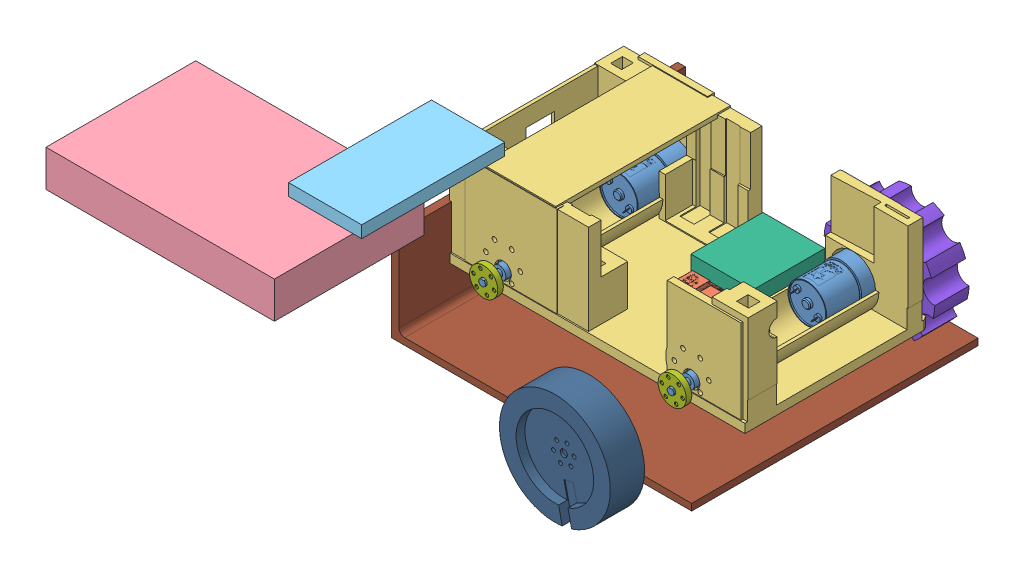
SolidWorks assembly Body, configuration Default. Lengths in mm.
Overall size (404.1 261.35 461.19).
19 component instances, 13 part files, 37 mates.
Components (placement in the parent):
- Pololu37DGearMotor-1: Pololu37DGearMotor [Default] at (433.1889 24.575 -2157.8681) x (-1 0 0) z (0 0 -1) size (36.8 36.8 107.9)
- Pololu37DGearMotor-2: Pololu37DGearMotor [Default] at (393.3389 24.575 -2043.7181) size (36.8 36.8 107.9)
- Part2-1: Part2 [Default] at origin
- Pololu37DGearMotor-3: Pololu37DGearMotor [Default] at (603.1889 24.575 -2157.8681) x (-1 0 0) z (0 0 -1) size (36.8 36.8 107.9)
- Pololu37DGearMotor-4: Pololu37DGearMotor [Default] at (563.3389 24.575 -2043.7181) size (36.8 36.8 107.9)
- RaspberryPi3-1: RaspberryPi3 [Default] at (530.3567 10.1 -2115.1676) x (0 0 1) z (0 1 0) size (89.64 57.31 18.92)
- Chassis3-1: Chassis3 [Default] at (583.2639 24.575 -2100.7931) x (-1 0 0) z (0 0 1) size (295.52 97.94 165.35)
- MaxoakPowerBank-1: MaxoakPowerBank [Default] at (250.8001 124.5785 -1906.0153) x (0 0 1) z (-1 0 0) size (135 33 206)
- MotoX-1: MotoX [Default] at (449.4488 208.455 -1791.0614) size (66.04 10.84 128.96)
- AdafruitMotorHat-1: AdafruitMotorHat [Default] at (560.7674 37.34 -2163.6096) x (0 0 1) z (1 0 0) size (65 13 56)
- Cover-1: Cover [Default] at (-302.6975 -256.127 -1471.0702) size (214.11 90 180) (hidden)
- PololuHub-2: PololuHub [Default] at (413.264 17.575 -2195.7931) x (-0.300118 -0.953902 0) z (0 0 1) size (25.4 25.4 9.2)
- PololuHub-3: PololuHub [Default] at (583.2638 17.575 -2195.7931) x (0.866025 0.5 0) z (0 0 1) size (25.4 25.4 9.2)
- PololuHub-4: PololuHub [Default] at (413.2639 17.5751 -2005.7931) x (-0.951824 -0.306645 0) z (0 0 -1) size (25.4 25.4 9.2)
- PololuHub-5: PololuHub [Default] at (583.2639 17.5751 -2005.7931) x (-0.927502 -0.373818 0) z (0 0 -1) size (25.4 25.4 9.2)
- HighTractionWheel-2: HighTractionWheel [Default] at (583.2639 17.575 -2221.1531) x (0 0 1) z (0.976357 -0.216166 0) size (30.86 100 100)
- MachineScrew4-40-1: MachineScrew4-40 [Default] at (588.0289 9.3218 -2211.1531) x (-0.989414 -0.145117 0) z (-0.145117 0.989414 0) size (5.02 20.48 5.02)
- Wheel-3: Wheel [Default] at (583.2639 17.575 -1928.3853) x (0 0 1) z (-1 0 0) size (30.86 100 100)
- ChargingDock-2: ChargingDock [Default] at (621.4227 -38.425 -2210.9825) size (270.89 86 258.22)
Mates (geometry in assembly coordinates):
- Coincident2: coincident anti-aligned: line of Pololu37DGearMotor-1 through (413.2639 17.575 -2177.7931) axis (0 0 -1); line of Pololu37DGearMotor-2 through (413.2639 17.575 -2023.7931) axis (0 0 1)
- Coincident8: coincident anti-aligned: line of Pololu37DGearMotor-3 through (583.2639 17.575 -2177.7931) axis (0 0 -1); line of Pololu37DGearMotor-4 through (583.2639 17.575 -2023.7931) axis (0 0 1)
- Coincident9: coincident aligned: line of Pololu37DGearMotor-3 through (583.2639 24.575 -2123.4931) axis (0 0 1); line of Chassis3-1 through (583.2639 24.575 -2100.7931) axis (0 0 1)
- Coincident10: coincident anti-aligned: line of Pololu37DGearMotor-4 through (583.2639 24.575 -2078.0931) axis (0 0 -1); line of Chassis3-1 through (583.2639 24.575 -2100.7931) axis (0 0 1)
- Coincident11: coincident aligned: line of Pololu37DGearMotor-1 through (413.2639 24.575 -2123.4931) axis (0 0 1); line of Chassis3-1 through (413.2639 24.575 -2100.7931) axis (0 0 1)
- Coincident12: coincident anti-aligned: line of Pololu37DGearMotor-2 through (413.2639 24.575 -2078.0931) axis (0 0 -1); line of Chassis3-1 through (413.2639 24.575 -2100.7931) axis (0 0 1)
- Distance1: distance = 27.57 mm anti-aligned: plane of RaspberryPi3-1 through (560.7674 9.77 -2078.6854) normal (0 -1 0); plane of AdafruitMotorHat-1 through (560.7674 37.34 -2163.6096) normal (0 1 0)
- Coincident17: coincident aligned: plane of RaspberryPi3-1 through (550.4322 9.34 -2073.3322) normal (1 0 0); plane of AdafruitMotorHat-1 through (550.4322 24.34 -2155.2664) normal (1 0 0)
- Coincident18: coincident aligned: plane of RaspberryPi3-1 through (547.4422 9.34 -2155.2664) normal (0 0 -1); plane of AdafruitMotorHat-1 through (550.4322 24.34 -2155.2664) normal (0 0 -1)
- Parallel4: parallel aligned: plane of MaxoakPowerBank-1 through (456.8001 157.5785 -1906.0153) normal (1 0 0); plane of assembly through (0 0 0) normal (1 0 0)
- Parallel5: parallel anti-aligned: plane of Chassis3-1 through (583.2639 24.575 -2180.7931) normal (0 0 -1); plane of assembly through (0 0 0) normal (0 0 1)
- Coincident33: coincident: point of Pololu37DGearMotor-3; line of Chassis3-1 through (583.2639 17.575 -2100.7931) axis (0 0 1)
- Coincident34: coincident anti-aligned: line of Pololu37DGearMotor-1 through (413.2639 17.575 -2177.7931) axis (0 0 -1); line of PololuHub-2 through (413.2639 17.575 -2204.6431) axis (0 0 1)
- Coincident35: coincident anti-aligned: line of Pololu37DGearMotor-2 through (413.2639 17.575 -2023.7931) axis (0 0 1); line of PololuHub-4 through (413.2639 17.575 -1996.9431) axis (0 0 -1)
- Coincident36: coincident anti-aligned: line of Pololu37DGearMotor-4 through (583.2639 17.575 -2023.7931) axis (0 0 1); line of PololuHub-5 through (583.2639 17.575 -1996.9431) axis (0 0 -1)
- Coincident38: coincident anti-aligned: plane of Chassis3-1 through (498.2639 0 -2100.7931) normal (0 -1 0); plane of assembly through (0 0 0) normal (0 1 0)
- Coincident39: coincident anti-aligned: line of Pololu37DGearMotor-3 through (583.2639 17.575 -2199.7931) axis (0 0 -1); line of PololuHub-3 through (583.2639 17.575 -2204.6431) axis (0 0 1)
- Parallel6: parallel aligned: plane of Pololu37DGearMotor-1; plane of assembly through (0 0 0) normal (0 1 0)
- Coincident41: coincident anti-aligned: plane of Pololu37DGearMotor-3 through (583.2639 24.575 -2177.7931) normal (0 0 -1); plane of Chassis3-1 through (583.2639 24.575 -2177.7931) normal (0 0 1)
- Coincident42: coincident anti-aligned: plane of Pololu37DGearMotor-4 through (583.2639 24.575 -2023.7931) normal (0 0 1); plane of Chassis3-1 through (583.2639 24.575 -2023.7931) normal (0 0 -1)
- Coincident43: coincident anti-aligned: plane of Pololu37DGearMotor-1 through (413.2639 24.575 -2177.7931) normal (0 0 -1); plane of Chassis3-1 through (413.2639 24.575 -2177.7931) normal (0 0 1)
- Coincident44: coincident anti-aligned: plane of Pololu37DGearMotor-2 through (413.2639 24.575 -2023.7931) normal (0 0 1); plane of Chassis3-1 through (413.2639 24.575 -2023.7931) normal (0 0 -1)
- Distance3: distance = 1.5 mm aligned: plane of PololuHub-5 through (583.2639 17.575 -2003.2931) normal (0 0 1); plane of Pololu37DGearMotor-4 through (583.2639 17.575 -2001.7931) normal (0 0 1)
- Distance4: distance = 1.5 mm aligned: plane of PololuHub-4 through (413.2639 17.575 -2003.2931) normal (0 0 1); plane of Pololu37DGearMotor-2 through (413.2639 17.575 -2001.7931) normal (0 0 1)
- Distance5: distance = 1.5 mm aligned: plane of PololuHub-3 through (583.2639 17.575 -2198.2931) normal (0 0 -1); plane of Pololu37DGearMotor-3 through (583.2639 17.575 -2199.7931) normal (0 0 -1)
- Distance6: distance = 1.5 mm aligned: plane of PololuHub-2 through (413.2639 17.575 -2198.2931) normal (0 0 -1); plane of Pololu37DGearMotor-1 through (413.2639 17.575 -2199.7931) normal (0 0 -1)
- Perpendicular1: perpendicular: plane of Pololu37DGearMotor-3 through (583.2639 19.975 -2187.7931) normal (0 1 0); line of PololuHub-3 through (583.2639 29.925 -2191.1931) axis (0 -1 0)
- Parallel11: parallel: plane of Pololu37DGearMotor-3 through (583.2639 19.975 -2187.7931) normal (0 1 0); line of HighTractionWheel-2 through (592.7939 17.575 -2221.1531) axis (-1 0 0)
- Coincident54: coincident anti-aligned: plane of PololuHub-3 through (583.2639 17.575 -2198.2931) normal (0 0 -1); plane of HighTractionWheel-2 through (583.2639 17.575 -2198.2931) normal (0 0 1)
- Concentric1: concentric anti-aligned: cylinder of PololuHub-3 through (583.2639 17.575 -2193.2931) axis (0 0 -1) radius 12.7; cylinder of HighTractionWheel-2 through (583.2639 17.575 -2200.2931) axis (0 0 1) radius 3.2
- Concentric2: concentric aligned: circle of HighTractionWheel-2; cylinder of MachineScrew4-40-1 through (588.0289 9.3218 -2192.6731) axis (0 0 -1) radius 1.335
- Coincident55: coincident anti-aligned: plane of HighTractionWheel-2 through (588.0289 9.3218 -2211.1531) normal (0 0 -1); plane of MachineScrew4-40-1 through (588.0289 9.3218 -2211.1531) normal (0 0 1)
- Concentric3: concentric anti-aligned: cylinder of Pololu37DGearMotor-4 through (583.2639 17.575 -2017.2931) axis (0 0 -1) radius 6; cylinder of Wheel-3 through (583.2639 17.575 -1907.5253) axis (0 0 1) radius 3.2
- Tangent1: tangent anti-aligned: cylinder of Wheel-3 through (583.2639 17.575 -1897.5253) axis (0 0 -1) radius 50; plane of ChargingDock-2 through (621.4227 -32.425 -2210.9825) normal (0 1 0)
- Parallel12: parallel aligned: plane of ChargingDock-2 through (621.4227 -32.425 -2210.9825) normal (0 1 0); plane of assembly through (0 0 0) normal (0 1 0)
- Coincident56: coincident anti-aligned: plane of RaspberryPi3-1 through (547.874 8 -2145.0003) normal (0 -1 0); plane of Chassis3-1 through (498.2639 8 -2100.7931) normal (0 1 0)
- Concentric5: concentric aligned: cylinder of RaspberryPi3-1 through (557.2674 11.1 -2102.1096) axis (0 1 0) radius 3; cylinder of Chassis3-1 through (557.2674 -2 -2102.1096) axis (0 1 0) radius 1.1452
